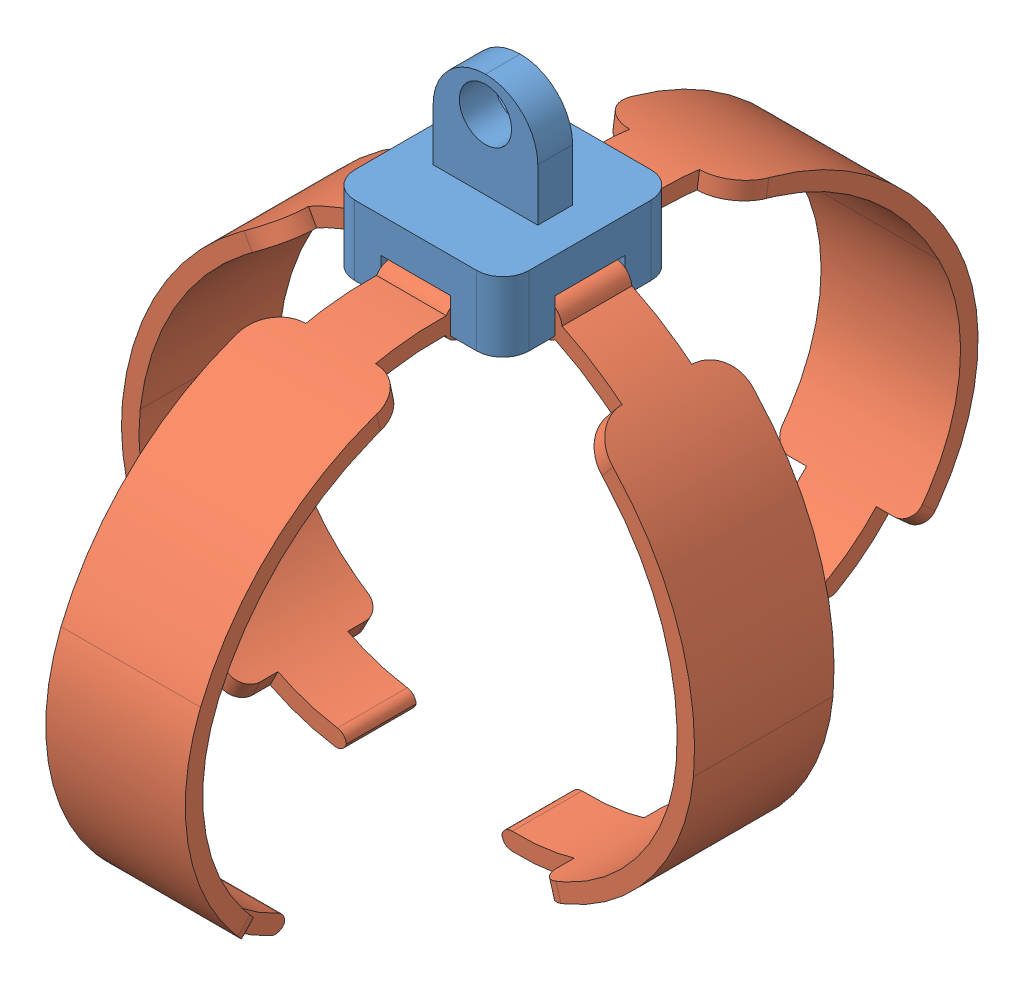
SolidWorks assembly Scoop Claw, configuration Default. Lengths in mm.
Overall size (177.01 220.76 265.71).
5 component instances, 2 part files, 8 mates.
Components (placement in the parent):
- Claw holder-1: Claw holder [Default] at (28.7861 47.1195 76.9465) size (50 100 50)
- Scoop Finger-1: Scoop Finger [Default] at (28.7861 -39.4075 20.7085) x (0 0.441781 -0.897123) z (1 0 0) size (65 142.42 41.13)
- Scoop Finger-2: Scoop Finger [Default] at (28.7861 -41.7189 128.0239) x (0 0.375192 0.926947) z (-1 0 0) size (65 142.42 41.13)
- Scoop Finger-3: Scoop Finger [Default] at (-0.5861 -47.0291 76.9465) x (-0.995465 0.095125 0) z (0 0 -1) size (65 142.42 41.13)
- Scoop Finger-4: Scoop Finger [Default] at (43.6832 -47.0543 76.9465) x (0.995791 -0.091649 0) z (0 0 1) size (65 142.42 41.13)
Mates (geometry in assembly coordinates):
- Concentric1: concentric anti-aligned: cylinder of Claw holder-1 through (50.7861 30.1195 59.8755) axis (0 0 1) radius 2.5; cylinder of Scoop Finger-4 through (50.7861 30.1195 96.9465) axis (0 0 -1) radius 2.5
- Coincident1: coincident anti-aligned: plane of Claw holder-1 through (53.7861 37.1195 66.9465) normal (0 0 1); plane of Scoop Finger-4 through (43.6832 -47.0543 66.9465) normal (0 0 -1)
- Concentric2: concentric anti-aligned: cylinder of Claw holder-1 through (45.8571 30.1195 98.9465) axis (-1 0 0) radius 2.5; cylinder of Scoop Finger-2 through (8.7861 30.1195 98.9465) axis (1 0 0) radius 2.5
- Coincident2: coincident anti-aligned: plane of Claw holder-1 through (18.7861 37.1195 101.9465) normal (1 0 0); plane of Scoop Finger-2 through (18.7861 -41.7189 128.0239) normal (-1 0 0)
- Concentric3: concentric aligned: cylinder of Claw holder-1 through (6.7861 30.1195 59.8755) axis (0 0 1) radius 2.5; cylinder of Scoop Finger-3 through (6.7861 30.1195 56.9465) axis (0 0 1) radius 2.5
- Coincident3: coincident anti-aligned: plane of Claw holder-1 through (3.7861 37.1195 86.9465) normal (0 0 -1); plane of Scoop Finger-3 through (-0.5861 -47.0291 86.9465) normal (0 0 1)
- Concentric4: concentric anti-aligned: cylinder of Claw holder-1 through (11.715 30.1195 54.9465) axis (1 0 0) radius 2.5; cylinder of Scoop Finger-1 through (48.7861 30.1195 54.9465) axis (-1 0 0) radius 2.5
- Coincident4: coincident anti-aligned: plane of Claw holder-1 through (38.7861 37.1195 51.9465) normal (-1 0 0); plane of Scoop Finger-1 through (38.7861 -39.4075 20.7085) normal (1 0 0)
